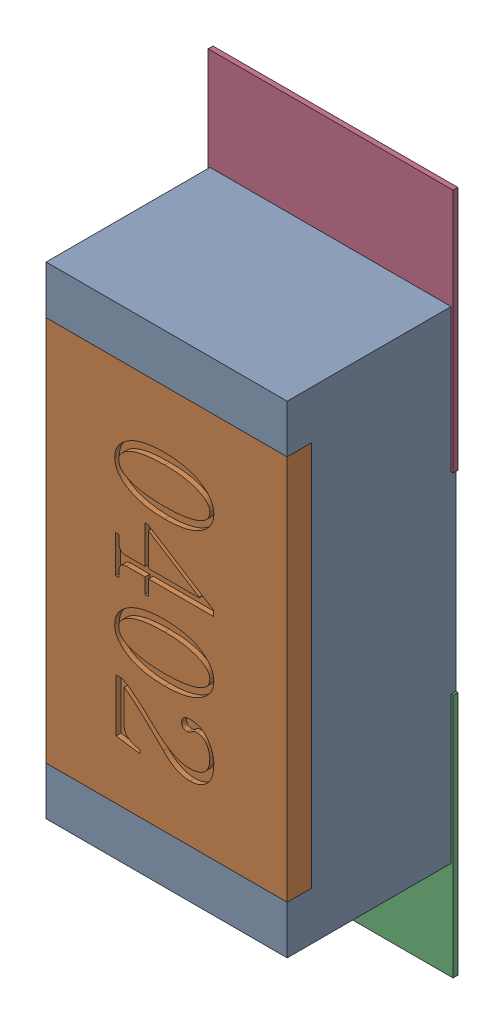
SolidWorks assembly R29, configuration Défaut. Lengths in mm.
Overall size (0.51 1.42 0.35).
5 component instances, 2 part files, 0 mates.
Components (placement in the parent):
- R0402-1: R0402 [Défaut] at (14.1223 -20.9415 0) x (0 -1 0) z (0 0 1) size (1 0.5 0.35)
- 6504207776-1: 6504207776 [Défaut] at (14.1224 -21.3915 0) size (0.51 0.51 0.01)
  - Extruded-1: Extruded [Défaut] at origin size (0.51 0.51 0.01)
- 6504207776-2: 6504207776 [Défaut] at (14.1224 -20.4844 0) size (0.51 0.51 0.01)
  - Extruded-1: Extruded [Défaut] at origin size (0.51 0.51 0.01)
